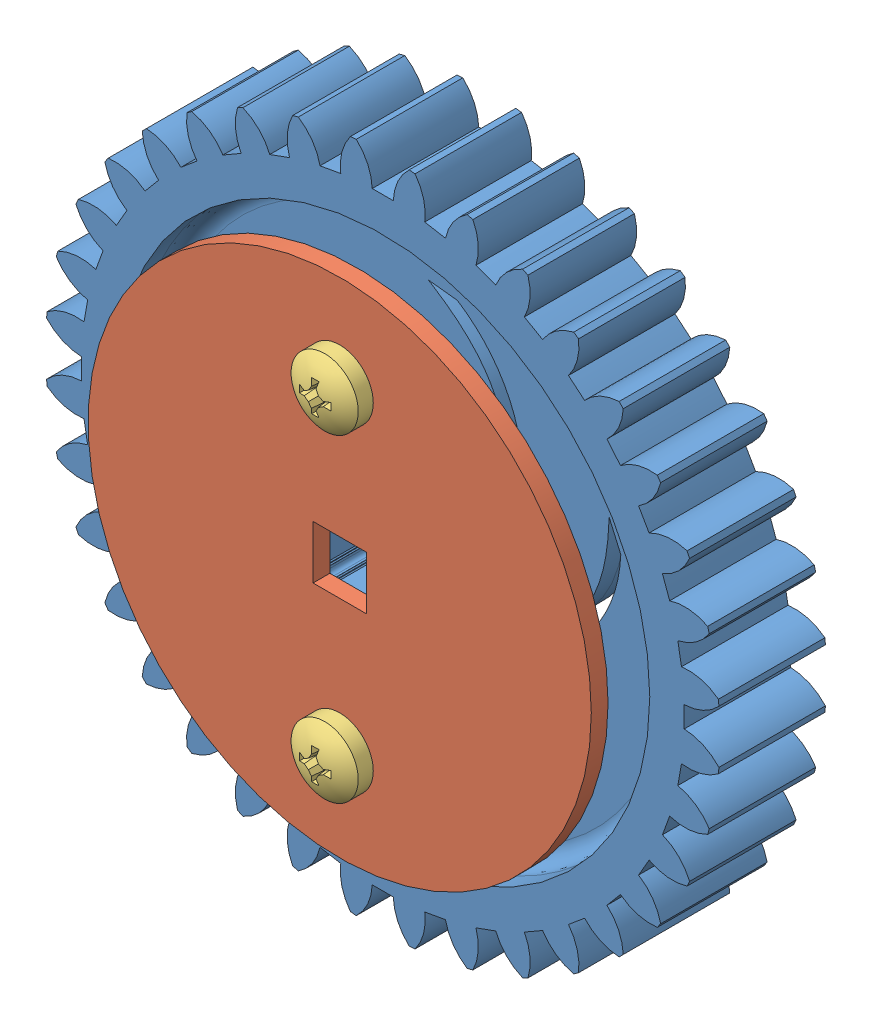
SolidWorks assembly reinforced 36T spur gear, configuration Default. Lengths in mm.
Overall size (40.08 40.08 12.1).
4 component instances, 3 part files, 7 mates.
Components (placement in the parent):
- Modified 36T gear-1: Modified 36T gear [36 teeth] at (13.4944 28.6707 27.2637) size (40.08 40.08 9.53)
- double plate 36T gear-1: double plate 36T gear [Default] at (13.5169 28.6932 33.0262) size (30 30 1)
- Tapping screw DIN 7049-ST2.2x9.5-C-H-S-1: Tapping screw DIN 7049-ST2.2x9.5-C-H-S [Tapping screw DIN 7049-ST2.2x9.5-C-H-S] at (13.5169 38.1932 33.0262) x (0 0 -1) z (1 0 0) size (11.07 4 4)
- Tapping screw DIN 7049-ST2.2x9.5-C-H-S-2: Tapping screw DIN 7049-ST2.2x9.5-C-H-S [Tapping screw DIN 7049-ST2.2x9.5-C-H-S] at (13.5169 19.1932 33.0262) x (0 0 -1) z (1 0 0) size (11.07 4 4)
Mates (geometry in assembly coordinates):
- Coincident3: coincident anti-aligned: plane of Modified 36T gear-1 through (13.4944 28.6707 32.0262) normal (0 0 1); plane of double plate 36T gear-1 through (13.5169 28.6932 32.0262) normal (0 0 -1)
- Coincident4: coincident anti-aligned: line of Modified 36T gear-1 through (15.1069 29.6228 32.0262) axis (0 -1 0); line of double plate 36T gear-1 through (15.1069 27.1032 32.0262) axis (0 1 0)
- Coincident5: coincident anti-aligned: line of Modified 36T gear-1 through (12.5423 30.2832 32.0262) axis (1 0 0); line of double plate 36T gear-1 through (15.1069 30.2832 32.0262) axis (-1 0 0)
- Concentric1: concentric aligned: cylinder of double plate 36T gear-1 through (13.5169 38.1932 32.0262) axis (0 0 1) radius 1.1; cylinder of Self tapping screw-1 through (13.5169 38.1932 33.0262) axis (0 0 1) radius 1.1
- Coincident6: coincident anti-aligned: plane of double plate 36T gear-1 through (13.5169 28.6932 33.0262) normal (0 0 1); plane of Self tapping screw-1 through (13.5169 39.2932 33.0262) normal (0 0 -1)
- Concentric21: concentric aligned: cylinder of double plate 36T gear-1 through (13.5169 19.1932 32.0262) axis (0 0 1) radius 1.1; cylinder of Self tapping screw-2 through (13.5169 19.1932 33.0262) axis (0 0 1) radius 1.1
- Coincident71: coincident anti-aligned: plane of double plate 36T gear-1 through (13.5169 28.6932 33.0262) normal (0 0 1); plane of Self tapping screw-2 through (13.5169 20.2932 33.0262) normal (0 0 -1)
